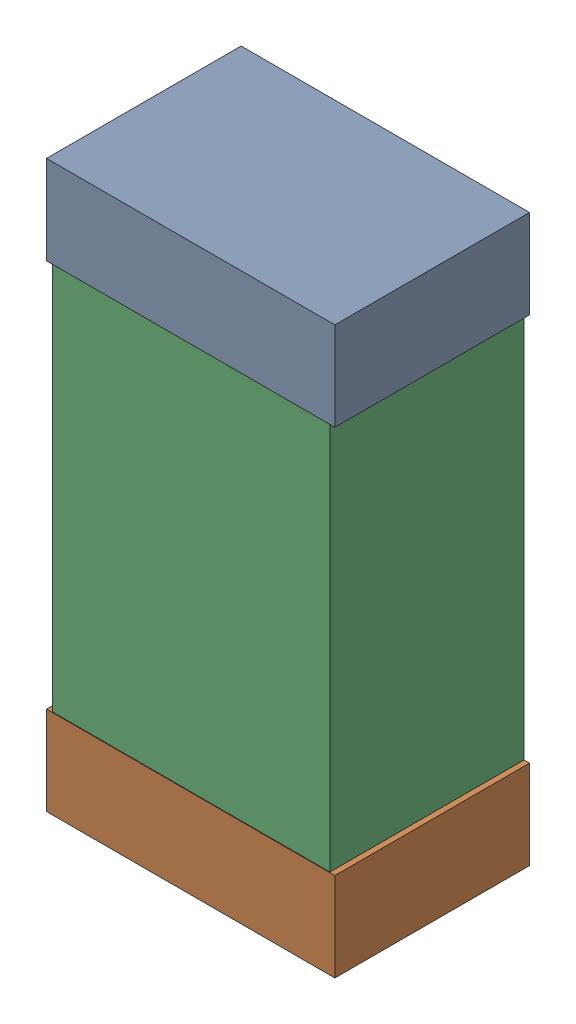
SolidWorks assembly C36, configuration Default. Lengths in mm.
Overall size (0.52 1.02 0.35).
6 component instances, 2 part files, 0 mates.
Components (placement in the parent):
- 870941120-1: 870941120 [Default] at (41.666 26.961 0) size (0.52 0.16 0.35)
  - Extruded_3-1: Extruded_3 [Default] at origin size (0.52 0.16 0.35)
- 870941120-2: 870941120 [Default] at (41.666 26.101 0) size (0.52 0.16 0.35)
  - Extruded_3-1: Extruded_3 [Default] at origin size (0.52 0.16 0.35)
- 870941280-1: 870941280 [Default] at (41.666 26.531 0) size (0.5 1 0.35)
  - Extruded_4-1: Extruded_4 [Default] at origin size (0.5 1 0.35)
